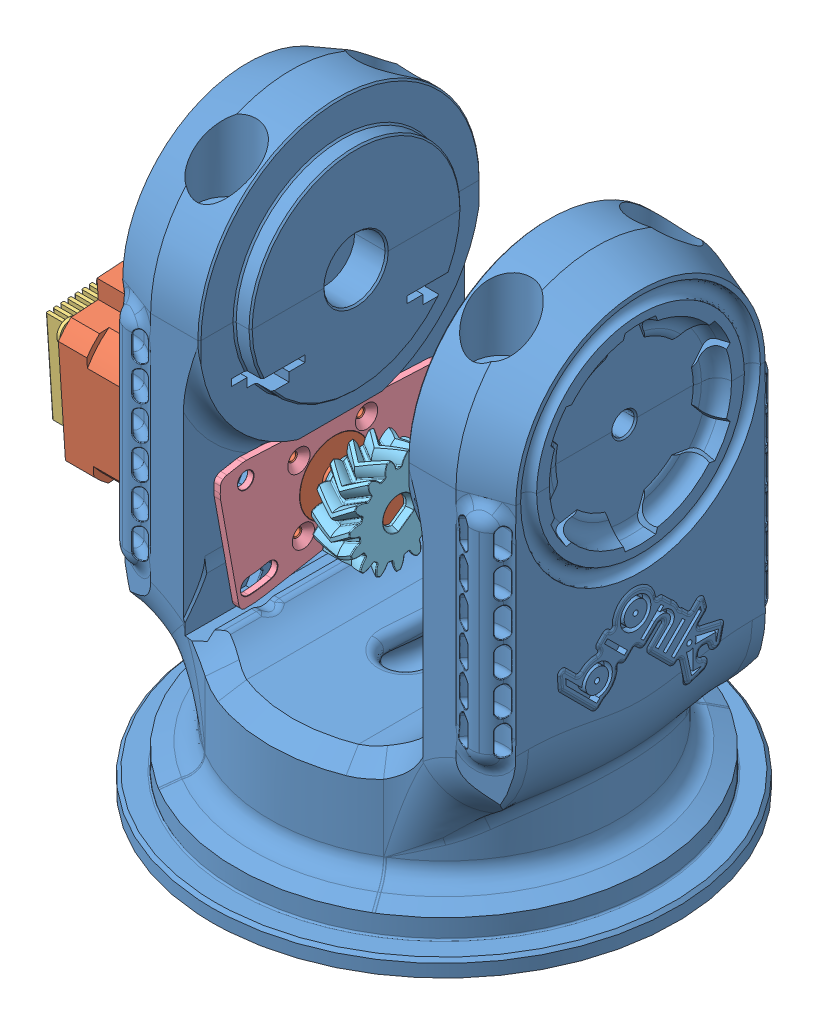
SolidWorks assembly 3 RotatingBase, configuration Domyślna. Lengths in mm.
Overall size (183 171 145).
18 component instances, 13 part files, 21 mates.
Components (placement in the parent):
- 3.1 Structure-1: 3.1 Structure [Domyślna] at origin size (145 196 145)
  - 3.1.1 RotatingBase-1: 3.1.1 RotatingBase [Domyślna] at origin size (145 171 145)
  - 3.1.2 Plug-1: 3.1.2 Plug [Domyślna] at (-43 152 25) size (21 18.06 23.49) (hidden)
  - 3.1.2 Plug-2: 3.1.2 Plug [Domyślna] at (43 152 -25) x (-1 0 0) z (0 0 -1) size (21 18.06 23.49) (hidden)
  - 3.1.2 Plug-3: 3.1.2 Plug [LustroDomyślna] at (-43 152 -25) size (21 18.06 23.49) (hidden)
  - 3.1.2 Plug-4: 3.1.2 Plug [LustroDomyślna] at (43 152 25) x (-1 0 0) z (0 0 -1) size (21 18.06 23.49) (hidden)
  - 3.1.4 Limiter-1: 3.1.4 Limiter [Domyślna] at (-21.6678 20 19.8979) x (0 0 1) z (1 0 0) size (15 45 15) (hidden)
  - 3.1.5 CableSeparator-1: 3.1.5 CableSeparator [Domyślna] at (0 43 0) size (21.21 42.77 89.34) (hidden)
- 3.2 MotorAssembly-1: 3.2 MotorAssembly [Domyślna] at (-35 85 0) x (0 0 -1) z (-1 0 0) size (72.38 50.68 95.72)
  - 3.2.1 Nema 17 planetary-1: 3.2.1 Nema 17 planetary [Domyślna] at (0.9135 18.1766 64.5) x (-0.997797 0.066338 0) z (-0.066338 -0.997797 0) size (42 82 48)
  - 3.2.2 radiator-1: 3.2.2 radiator [Domyślna] at (0.9135 18.1766 64.5) x (-0.066338 -0.997797 0) z (-0.997797 0.066338 0) size (40.94 11 40.94)
  - 3.2.3 StaticSheet-1: 3.2.3 StaticSheet [Domyślna] at (0 20 0) x (1 0 0) z (0 0 -1) size (70 40 2) (hidden)
  - 3.2.4 MovingSheet-1: 3.2.4 MovingSheet [Domyślna] at (0.9135 18.1766 2) x (0.997797 -0.066338 0) z (0 0 -1) size (69.88 40 2)
  - 3.2.5 ISO - LH Helical gear 1.5M 15T 37HA 20PA 6FW ---15A75H50L8.0N-1: 3.2.5 ISO - LH Helical gear 1.5M 15T 37HA 20PA 6FW ---15A75H50L8.0N [ISO - LH Helical gear 1.5M 15T 37HA 20PA 6FW ---15A75H50L8.0N] at (0.9135 18.1766 -20) x (0 0 1) z (-0.816827 0.576882 0) size (17.22 31.23 31.24)
- 3.4.1 Encoder holder-1: 3.4.1 Encoder holder [Domyślna] at (-61.5 127 0) x (0 0 -1) z (1 0 0) size (40 60 25.11)
- 2.4.1 Encoder_main_housing-1: 2.4.1 Encoder_main_housing [Domyślna] at (-61.5 127 0) x (0 0 -1) z (0 1 0) size (23 21.6 23)
- podstawa_plan-1: podstawa_plan [Domyślna] at (0 48 0) size (86.08 202.14 94) (hidden)
- Wsuwka na silnik2-1: Wsuwka na silnik2 [Domyślna] at (-37 66.8234 -0.9135) size (28 40.7 45.46) (hidden)
Mates (geometry in assembly coordinates):
- Wspólnie34: coincident anti-aligned: plane of 3.1 Structure-1/3.1.1 RotatingBase-1 through (-60.5 0 0) normal (-1 0 0); plane of 3.2 MotorAssembly-1/3.2.1 Nema 17 planetary-1 through (-60.5 66.8234 -0.9135) normal (1 0 0)
- Wspólnie35: coincident anti-aligned: plane of 3.1 Structure-1/3.1.1 RotatingBase-1 through (-56.5 127 0) normal (-1 0 0); plane of 3.4.1 Encoder holder-1 through (-56.5 127 0) normal (1 0 0)
- Koncentryczne35: concentric anti-aligned: cylinder of 3.1 Structure-1/3.1.1 RotatingBase-1 through (-72.501 127 0) axis (1 0 0) radius 3.5; cylinder of 3.4.1 Encoder holder-1 through (-56.5 127 0) axis (-1 0 0) radius 6.2
- Koncentryczne36: concentric anti-aligned: circle of 3.1 Structure-1/3.1.1 RotatingBase-1; cylinder of 3.4.1 Encoder holder-1 through (-56.5 150 0) axis (-1 0 0) radius 7
- Koncentryczne37: concentric aligned: cylinder of 3.1 Structure-1/3.1.1 RotatingBase-1 through (-44.7 50.5913 24.6938) axis (-1 0 0) radius 3.7; cylinder of 3.2 MotorAssembly-1/3.2.3 StaticSheet-1 through (-33 50.5913 24.6938) axis (-1 0 0) radius 2.5
- Wspólnie36: coincident anti-aligned: plane of 3.1 Structure-1/3.1.1 RotatingBase-1 through (-37 0 72.5) normal (1 0 0); plane of 3.2 MotorAssembly-1/3.2.4 MovingSheet-1 through (-37 47.7381 29.8883) normal (-1 0 0)
- Koncentryczne38: concentric aligned: cylinder of 3.1 Structure-1/3.1.1 RotatingBase-1 through (-60.5 79.6667 27) axis (-1 0 0) radius 2.5; cylinder of 3.2 MotorAssembly-1/3.2.4 MovingSheet-1 through (-35 79.6667 27) axis (-1 0 0) radius 2.5
- Wspólnie37: coordinate: point of 3.1 Structure-1/3.1.1 RotatingBase-1
- Koncentryczne39: concentric anti-aligned: cylinder of 3.4.1 Encoder holder-1 through (-56.499 134.3612 4.25) axis (-1 0 0) radius 1.1; cylinder of 2.4.1 Encoder_main_housing-1 through (-61.5 134.3612 4.25) axis (1 0 0) radius 1.1
- Koncentryczne40: concentric anti-aligned: cylinder of 3.4.1 Encoder holder-1 through (-56.499 119.6388 -4.25) axis (-1 0 0) radius 1.1; cylinder of 2.4.1 Encoder_main_housing-1 through (-61.5 119.6388 -4.25) axis (1 0 0) radius 1.1
- Wspólnie38: coincident anti-aligned: plane of 3.4.1 Encoder holder-1 through (-61.5 127 0) normal (-1 0 0); plane of 2.4.1 Encoder_main_housing-1 through (-61.5 127 0) normal (1 0 0)
- Koncentryczne41: concentric: cylinder of 3.1 Structure-1/3.1.1 RotatingBase-1 through (37.5 127 0) axis (-1 0 0) radius 9.6; line of podstawa_plan-1 through (75 37.5 127) axis (0 -1 0)
- Wspólnie39: coincident: plane of podstawa_plan-1 through (0 48 0) normal (1 0 0); plane of assembly through (0 0 0) normal (1 0 0)
- Równolegle1: parallel: plane of podstawa_plan-1 through (0 48 0) normal (0 1 0); plane of assembly through (0 0 0) normal (0 1 0)
- Równolegle4: parallel: plane of 3.2 MotorAssembly-1/3.2.1 Nema 17 planetary-1 through (-60.5 47.2628 -23.2603) normal (0 -0.997797 -0.066338); plane of podstawa_plan-1 through (0 48 0) normal (0 1 0)
- Wspólnie43: coincident: plane of 3.2 MotorAssembly-1/3.2.1 Nema 17 planetary-1 through (-37 66.8234 -0.9135) normal (1 0 0); plane of podstawa_plan-1 through (-37.5 48 0) normal (-1 0 0)
- Limit odległości1: limit distance = 0 mm: plane of 3.2 MotorAssembly-1/3.2.1 Nema 17 planetary-1 through (-99.5 66.8234 -0.9135) normal (0 -0.066338 0.997797); plane of podstawa_plan-1 through (0 48 0) normal (0 0 1)
- Wspólnie44: coincident: plane of 3.2 MotorAssembly-1/3.2.1 Nema 17 planetary-1 through (-99.5 66.8234 -0.9135) normal (0 0.997797 0.066338); plane of podstawa_plan-1 through (0 66 0) normal (0 1 0)
- Koncentryczne42: concentric anti-aligned: cylinder of 3.2 MotorAssembly-1/3.2.1 Nema 17 planetary-1 through (-35 66.8234 -0.9135) axis (-1 0 0) radius 11; circle of Wsuwka na silnik2-1
- Wspólnie45: coincident anti-aligned: plane of 3.2 MotorAssembly-1/3.2.1 Nema 17 planetary-1 through (-37 66.8234 -0.9135) normal (1 0 0); plane of Wsuwka na silnik2-1 through (-37 86.0234 -16.9135) normal (-1 0 0)
- Równolegle5: parallel aligned: plane of Wsuwka na silnik2-1 through (-37 66.8234 -0.9135) normal (0 1 0); plane of assembly through (0 0 0) normal (0 1 0)
